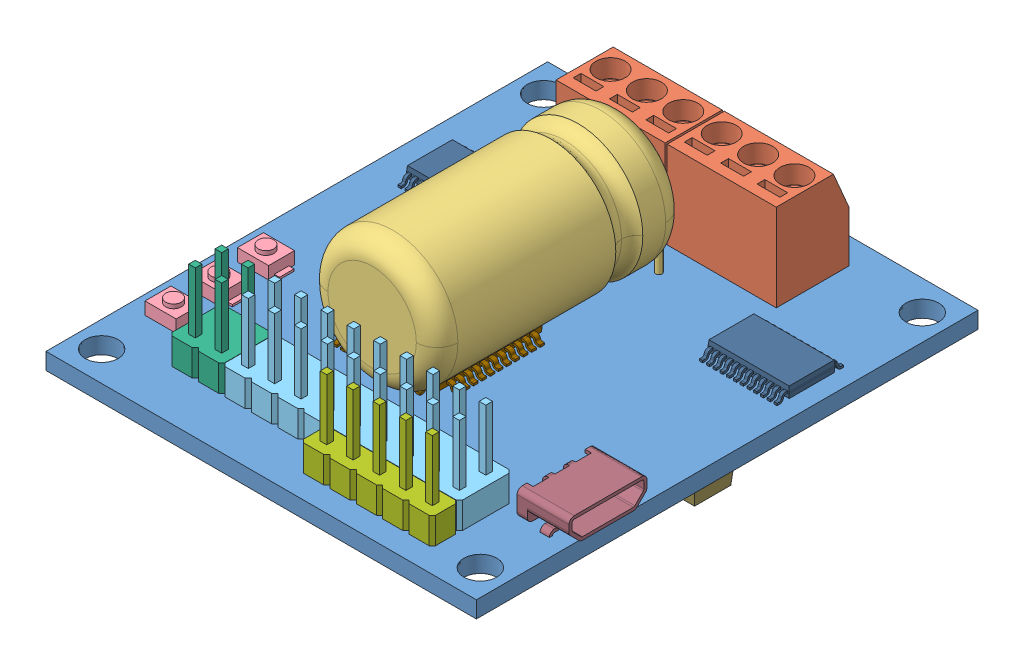
SolidWorks assembly roboclaw, configuration Default. Lengths in mm.
Overall size (41.74 17.25 48.29).
21 component instances, 13 part files, 0 mates.
Components (placement in the parent):
- MC5A-PCB-1: MC5A-PCB [Default] at (20.9892 37.9455 60.0095) size (41.43 1.6 48.29)
- ED2636-ND-1: ED2636-ND [Default] at (26.552 39.5455 41.8831) x (-1 0 0) z (0 0 -1) size (10.5 11.85 7)
- P5186-ND-1: P5186-ND [Default] at (20.6738 47.0944 49.1541) x (0 -1 0) z (-1 0 0) size (16.25 25.4 12.5)
- SW1020CT-ND-1: SW1020CT-ND [Default] at (3.5393 39.5455 75.1362) x (-1 0 0) z (0 0 -1) size (4 1.6 2.5)
- SW1020CT-ND-2: SW1020CT-ND [Default] at (3.5393 39.5455 70.7847) x (-1 0 0) z (0 0 -1) size (4 1.6 2.5)
- SW1020CT-ND-3: SW1020CT-ND [Default] at (3.5393 39.5455 66.2406) x (-1 0 0) z (0 0 -1) size (4 1.6 2.5)
- PBC09DAAN-1: PBC09DAAN [Default] at (13.6675 39.5455 76.8011) size (22.86 11.43 5.08)
- PBC02DAAN-1: PBC02DAAN [Default] at (8.5648 39.5455 76.8011) size (5.08 11.43 5.08)
- PBC05SAAN-1: PBC05SAAN [Default] at (23.7993 39.5455 80.6492) size (12.7 11.43 2.54)
- CRF2512-FV-R001ELFCT-ND-1: CRF2512-FV-R001ELFCT-ND [Default] at (24.0462 37.3455 53.7504) x (0 0 -1) z (1 0 0) size (6.4 0.6 3.2)
- CRF2512-FV-R001ELFCT-ND-2: CRF2512-FV-R001ELFCT-ND [Default] at (17.2574 37.3455 53.7504) x (0 0 -1) z (1 0 0) size (6.4 0.6 3.2)
- ATXMEGA32A4U-AU-ND-1: ATXMEGA32A4U-AU-ND [Default] at (17.74 39.7455 63.8454) x (0 0 -1) z (1 0 0) size (12 1.2 12)
- 620-1319-1-ND-1: 620-1319-1-ND [Default] at (7.2465 39.6955 50.308) size (7.8 1.2 6.4)
- 620-1319-1-ND-2: 620-1319-1-ND [Default] at (36.2731 39.6955 50.308) size (7.8 1.2 6.4)
- IRF7351TRPBFCT-ND-1: IRF7351TRPBFCT-ND [Default] at (35.3498 37.6966 49.3224) x (-1 0 0) z (0 0 1) size (5 1.75 6.2)
- IRF7351TRPBFCT-ND-2: IRF7351TRPBFCT-ND [Default] at (29.6688 37.6966 49.3224) x (-1 0 0) z (0 0 1) size (5 1.75 6.2)
- IRF7351TRPBFCT-ND-3: IRF7351TRPBFCT-ND [Default] at (11.941 37.6966 49.3224) x (-1 0 0) z (0 0 1) size (5 1.75 6.2)
- IRF7351TRPBFCT-ND-4: IRF7351TRPBFCT-ND [Default] at (6.1828 37.6966 49.3224) x (-1 0 0) z (0 0 1) size (5 1.75 6.2)
- LM340MPX-5.0_NOPBCT-ND-1: LM340MPX-5.0_NOPBCT-ND [Default] at (37.7534 37.8455 60.7041) x (0 0 -1) z (-1 0 0) size (7.3 1.8 6.7)
- ED2636-ND-2: ED2636-ND [Default] at (15.8491 39.5455 41.8831) x (-1 0 0) z (0 0 -1) size (10.5 11.85 7)
- 609-4618-1-ND-1: 609-4618-1-ND [Default] at (42.0202 40.9455 71.8007) x (0 0 -1) z (1 0 0) size (7.5 3.05 5)
